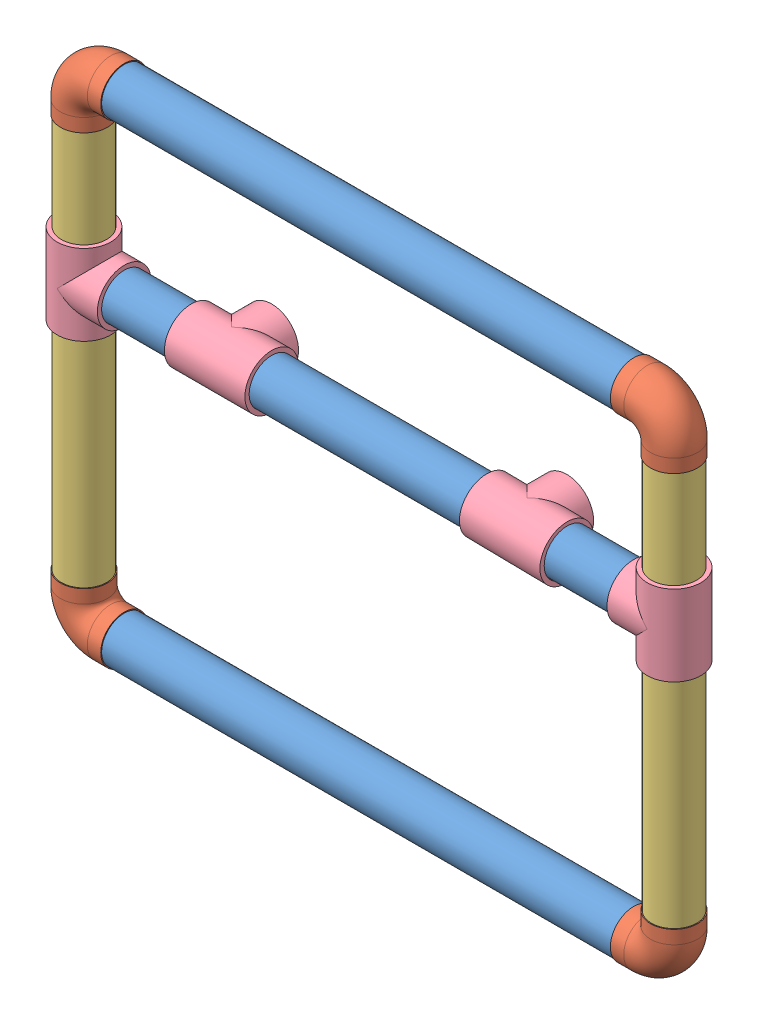
SolidWorks assembly structure_tube_left, configuration Default. Lengths in mm.
Overall size (304.8 247.2 38.88).
13 component instances, 4 part files, 23 mates.
Components (placement in the parent):
- PVC_tube_12in-1: PVC_tube_12in [Default] at (224.9643 139.1096 188.8412) size (254 21.34 21.34)
- PVC_90-1: PVC_90 [Default] at (-23.4538 156.2418 188.8412) size (30.16 30.16 22.23)
- PVC_90-2: PVC_90 [Default] at (220.532 157.3915 188.8412) x (0 1 0) z (0 0 1) size (30.16 30.16 22.23)
- PVC_tube_10in-1: PVC_tube_10in [Default] at (237.6643 148.181 188.8412) x (0 -1 0) z (-0.994803 0 0.101823) size (203.2 21.34 21.34)
- PVC_90-3: PVC_90 [Default] at (219.3823 346.9488 188.8412) x (-1 0 0) z (0 0 1) size (30.16 30.16 22.23)
- PVC_tube_12in-2: PVC_tube_12in [Default] at (224.9643 364.081 188.8412) x (1 0 0) z (0 0 1) size (254 21.34 21.34)
- PVC_90-4: PVC_90 [Default] at (-24.6035 345.7991 188.8412) x (0 -1 0) z (0 0 1) size (30.16 30.16 22.23)
- PVC_tube_10in-2: PVC_tube_10in [Default] at (-41.7357 351.381 188.8412) x (0 1 0) z (-0.97697 0 0.213378) size (203.2 21.34 21.34)
- PVC_tee-1: PVC_tee [Default] at (-41.7357 279.749 188.8412) x (0 -1 0) z (0 0 1) size (38.1 38.88 25.4)
- PVC_tee-2: PVC_tee [Default] at (237.6643 279.749 188.8412) x (0 1 0) z (0 0 1) size (38.1 38.88 25.4)
- PVC_tee-4: PVC_tee [Default] at (28.1143 279.749 188.8412) x (1 0 0) z (0 1 0) size (38.1 38.88 25.4)
- PVC_tee-5: PVC_tee [Default] at (167.8143 279.749 188.8412) x (-0.999872 0.015996 0) z (-0.015996 -0.999872 0) size (38.1 38.88 25.4)
- PVC_tube_12in-3: PVC_tube_12in [Default] at (224.9643 279.749 188.8412) x (1 0 0) z (0 -0.082035 0.996629) size (254 21.34 21.34)
Mates (geometry in assembly coordinates):
- Concentric1: concentric anti-aligned: circle of PVC_90-1; circle of PVC_tube_10in-2
- Concentric2: concentric aligned: circle of PVC_90-4; circle of PVC_tube_10in-2
- Concentric3: concentric aligned: circle of PVC_tube_12in-1; circle of PVC_90-1
- Distance1: distance = 6.35 mm anti-aligned: plane of PVC_tube_12in-1 through (-29.0357 139.1096 188.8412) normal (-1 0 0); plane of PVC_90-1 through (-22.6857 139.1096 188.8412) normal (1 0 0)
- Concentric4: concentric anti-aligned: circle of PVC_tube_12in-1; circle of PVC_90-2
- Concentric5: concentric anti-aligned: circle of PVC_90-2; circle of PVC_tube_10in-1
- Concentric6: concentric aligned: circle of PVC_90-4; circle of PVC_tube_10in-2
- Distance2: distance = 6.35 mm anti-aligned: plane of PVC_90-4 through (-41.7357 345.031 188.8412) normal (0 -1 0); plane of PVC_tube_10in-2 through (-41.7357 351.381 188.8412) normal (0 1 0)
- Concentric7: concentric aligned: circle of PVC_tube_12in-2; circle of PVC_90-4
- Distance3: distance = 6.35 mm anti-aligned: plane of PVC_tube_12in-2 through (-29.0357 364.081 188.8412) normal (-1 0 0); plane of PVC_90-4 through (-22.6857 364.081 188.8412) normal (1 0 0)
- Distance4: distance = 6.35 mm anti-aligned: plane of PVC_90-3 through (218.6143 364.081 188.8412) normal (-1 0 0); plane of PVC_tube_12in-2 through (224.9643 364.081 188.8412) normal (1 0 0)
- Concentric8: concentric anti-aligned: circle of PVC_90-3; circle of PVC_tube_12in-2
- Concentric9: concentric anti-aligned: circle of PVC_tube_10in-1; circle of PVC_90-3
- Concentric10: concentric anti-aligned: cylinder of PVC_tube_10in-2 through (-41.7357 148.181 188.8412) axis (0 1 0) radius 10.668; circle of PVC_tee-1
- Coincident10: coincident aligned: line of PVC_tee-1 through (-41.7357 279.749 188.8412) axis (1 0 0); line of assembly
- Coincident11: coincident anti-aligned: line of PVC_tee-2 through (237.6643 279.749 188.8412) axis (-1 0 0); line of assembly
- Concentric11: concentric anti-aligned: cylinder of PVC_tube_10in-1 through (237.6643 351.381 188.8412) axis (0 -1 0) radius 10.668; circle of PVC_tee-2
- Perpendicular4: perpendicular: line of PVC_tee-5 through (167.8143 279.749 188.8412) axis (0 0 -1); line of assembly
- Perpendicular5: perpendicular: line of PVC_tee-4 through (28.1143 279.749 188.8412) axis (0 0 -1); line of assembly
- Coincident17: coincident: point of PVC_tee-4; line of assembly
- Coincident18: coincident: point of PVC_tee-5; line of assembly
- Concentric12: concentric: circle of PVC_tee-1; circle of PVC_tube_12in-3
- Distance5: distance = 6.35 mm anti-aligned: plane of PVC_tube_12in-3 through (-29.0357 279.749 188.8412) normal (-1 0 0); plane of PVC_tee-1 through (-22.6857 279.749 188.8412) normal (1 0 0)
